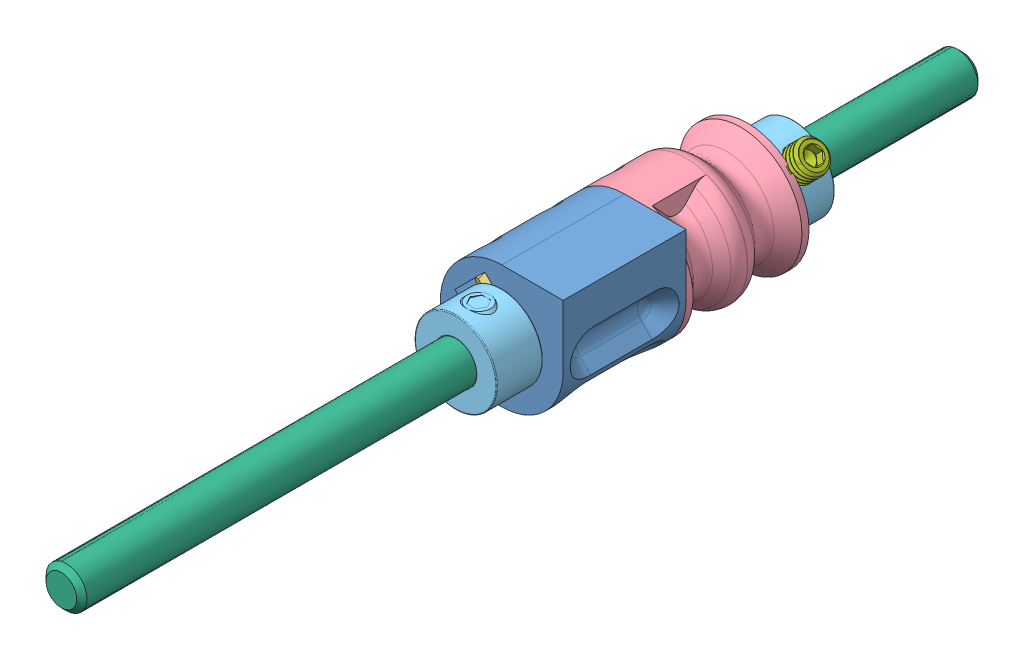
SolidWorks assembly Wing Fold Mechanism Rotating ASSY, configuration Default. Lengths in mm.
Overall size (19.05 19.05 139.7).
14 component instances, 7 part files, 0 mates.
Components (placement in the parent):
- Wing Fold Mechanism Rotary Detents-1: Wing Fold Mechanism Rotary Detents [Default] at origin size (19.05 19.05 19.05)
  - Wing Fold Mechanism Rotary Detents-1: Wing Fold Mechanism Rotary Detents [Default] at origin size (19.05 19.05 19.05)
  - 92311A105-1: 92311A105 [Default] at (-4.0904 4.0904 33.3375) x (0.707107 0.707107 0) z (-0.707107 0.707107 0) size (2.91 2.9 4.84)
  - 91841A005-1: 91841A005 [Default] at (-4.0972 4.0972 33.3375) x (0.707107 0.707107 0) z (0 0 1) size (6.35 2.56 7.33)
  - 92311A105-2: 92311A105 [Default] at (-4.0904 4.0904 23.8125) x (0.707107 0.707107 0) z (-0.707107 0.707107 0) size (2.91 2.9 4.84)
  - 91841A005-2: 91841A005 [Default] at (-4.0972 4.0972 23.8125) x (0.707107 0.707107 0) z (0 0 1) size (6.35 2.56 7.33)
- Wing Fold Mechanism Push-Pull Detents-1: Wing Fold Mechanism Push-Pull Detents [Default] at origin size (19.05 19.05 19.05)
  - Wing Fold Mechanism Push-Pull Detents-1: Wing Fold Mechanism Push-Pull Detents [Default] at origin size (19.05 19.05 19.05)
  - 91841A005-1: 91841A005 [Default] at (-4.0972 4.0972 14.2875) x (0.707107 0.707107 0) z (0 0 1) size (6.35 2.56 7.33)
  - 92311A105-1: 92311A105 [Default] at (-4.0904 4.0904 14.2875) x (0.707107 0.707107 0) z (-0.707107 0.707107 0) size (2.91 2.9 4.84)
- 9414T6-1: 9414T6 [Default] at (0 0 -3.5719) x (0.707107 -0.707107 0) z (0 0 1) size (12.7 12.7 7.15)
- 9414T6-2: 9414T6 [Default] at (0 0 41.6719) size (12.7 12.7 7.15)
- Wing Fold Mechanism .250 Shaft-1: Wing Fold Mechanism .250 Shaft [Default] at origin size (6.35 6.35 139.7)
- 92311A425-1: 92311A425 [Default] at (4.771 4.771 -3.5719) x (0.707107 -0.707107 0) z (0.707107 0.707107 0) size (4.96 4.83 6.49)
